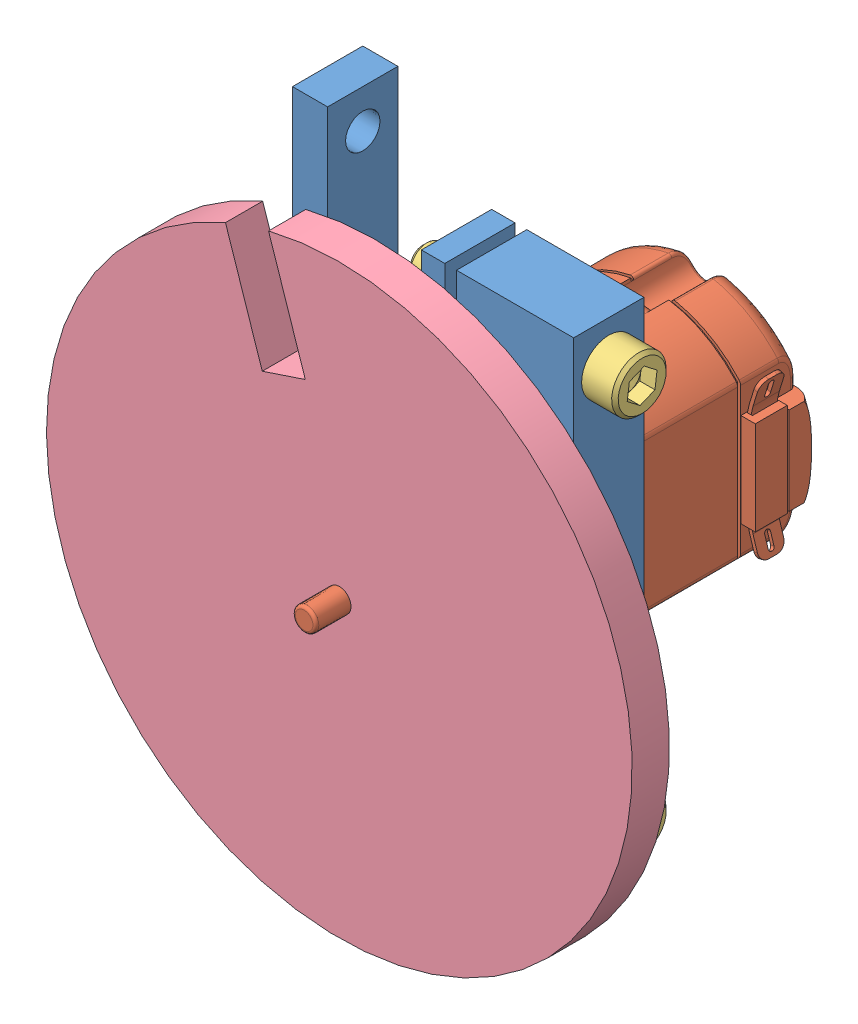
SolidWorks assembly MotorAssem, configuration Default. Lengths in mm.
Overall size (63.22 63.17 37.75).
5 component instances, 4 part files, 10 mates.
Components (placement in the parent):
- MotorMount-1: MotorMount [Default] at (15.7766 38.9912 50.9262) size (24 52.9 6)
- DCmotor-Size130-1: DCmotor-Size130 [Default] at (36.7766 38.9912 34.9262) size (16.47 19.75 37.75)
- socket head cap screw_ai-11: socket head cap screw_ai [HX-SHCS 0.112-40x0.625x0.625-N] at (50.1214 55.2437 53.9262) x (-1 0 0) z (0 0.924225 0.381849) size (18.72 4.65 4.65)
- socket head cap screw_ai-12: socket head cap screw_ai [HX-SHCS 0.112-40x0.625x0.625-N] at (50.1214 22.7387 53.9262) x (-1 0 0) z (0 0.924225 0.381849) size (18.72 4.65 4.65)
- InterruptWheel-1: InterruptWheel [Default] at (36.7766 38.9912 64.8387) x (0.948715 0.316133 0) z (0 0 1) size (50 49.92 3.17)
Mates (geometry in assembly coordinates):
- Coincident3: coincident aligned: plane of MotorMount-1 through (15.7766 38.9912 50.9262) normal (0 1 0); plane of DCmotor-Size130-1 through (36.7766 38.9912 34.9262) normal (0 1 0)
- Coincident4: coincident anti-aligned: plane of MotorMount-1 through (44.2766 38.9912 46.9262) normal (-1 0 0); plane of DCmotor-Size130-1 through (44.2766 35.2412 64.9262) normal (1 0 0)
- Concentric1: concentric anti-aligned: cylinder of MotorMount-1 through (36.7766 38.9912 46.9262) axis (0 0 1) radius 9.875; cylinder of DCmotor-Size130-1 through (36.7766 38.9912 59.9262) axis (0 0 -1) radius 9.875
- Concentric7: concentric anti-aligned: cylinder of MotorMount-1 through (51.4343 55.2437 53.9262) axis (-1 0 0) radius 1.47; cylinder of socket head cap screw_ai-11 through (81.8714 55.2437 53.9262) axis (1 0 0) radius 2.3241
- Coincident11: coincident anti-aligned: plane of MotorMount-1 through (47.2766 38.9912 46.9262) normal (1 0 0); plane of socket head cap screw_ai-11 through (47.2766 54.3562 56.0742) normal (-1 0 0)
- Concentric8: concentric anti-aligned: cylinder of MotorMount-1 through (51.4343 22.7387 53.9262) axis (-1 0 0) radius 1.47; cylinder of socket head cap screw_ai-12 through (81.8714 22.7387 53.9262) axis (1 0 0) radius 2.3241
- Coincident12: coincident anti-aligned: plane of MotorMount-1 through (47.2766 38.9912 46.9262) normal (1 0 0); plane of socket head cap screw_ai-12 through (47.2766 21.8513 56.0742) normal (-1 0 0)
- Concentric9: concentric aligned: circle of DCmotor-Size130-1; circle of InterruptWheel-1
- Distance1: distance = 3 mm aligned: plane of MotorMount-1 through (15.7766 38.9912 56.9262) normal (0 0 1); plane of DCmotor-Size130-1 through (36.7766 38.9912 59.9262) normal (0 0 1)
- Distance2: distance = 3 mm aligned: plane of InterruptWheel-1 through (36.7766 38.9912 66.4262) normal (0 0 1); plane of DCmotor-Size130-1 through (36.7766 38.9912 69.4262) normal (0 0 1)
